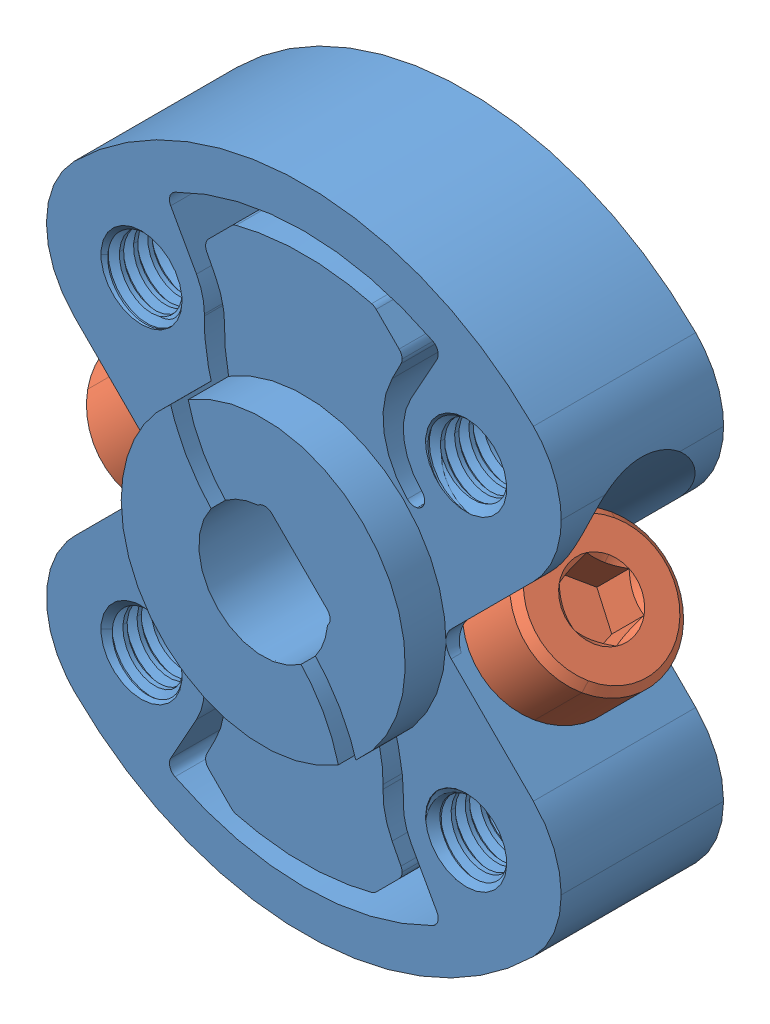
SolidWorks assembly 0.25 inch D-Bore Hub 1309-0016-1250, configuration Default. Lengths in mm.
Overall size (28.36 32 10.95).
3 component instances, 2 part files, 0 mates.
Components (placement in the parent):
- 1309-0016-1250.STEP-1: 1309-0016-1250.STEP [Default] at (-24.3704 7.8063 6.6176) size (25.38 32 10)
- 2800-0004-0014_90128A207.STEP-1: 2800-0004-0014_90128A207.STEP [Default] at (-26.4232 -3.3124 6.6176) x (0.5 -0.5 0.707107) z (-0.707107 -0.707107 0) size (7 7 18.01)
- 2800-0004-0014_90128A207.STEP-2: 2800-0004-0014_90128A207.STEP [Default] at (-22.3175 18.9251 6.6176) x (-0.5 0.5 0.707107) z (0.707107 0.707107 0) size (7 7 18.01)
